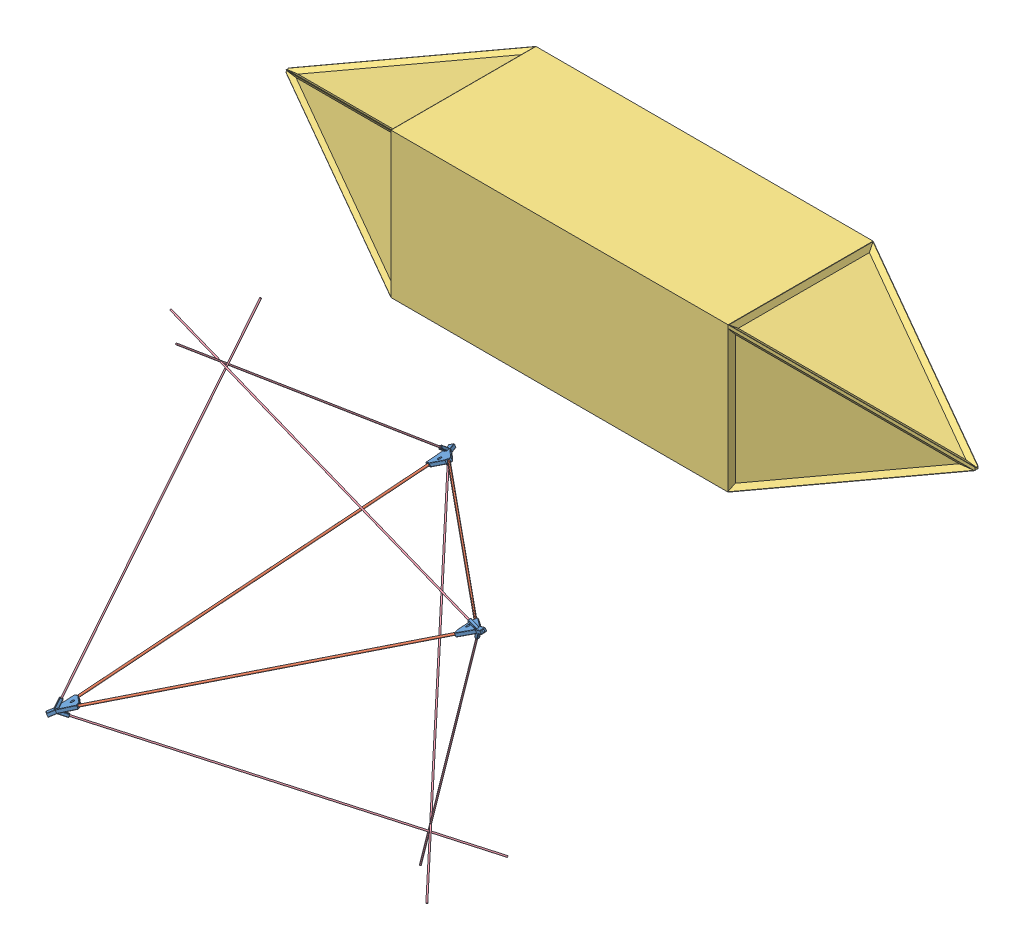
SolidWorks assembly Catastrophe, configuration Défaut. Lengths in mm.
Overall size (2044.4 1360.49 1572.81).
13 component instances, 4 part files, 22 mates.
Components (placement in the parent):
- pièceTriangle-1: pièceTriangle [Défaut] at (258.5913 881.7881 -1928.4174) x (0.355593 0.038555 0.933845) z (-0.425271 0.896403 0.124927) size (120.62 100 107.84)
- pièceTriangle-2: pièceTriangle [Défaut] at (138.1407 689.4914 -878.5931) x (0.542983 0.363125 -0.757172) z (0.425271 -0.896403 -0.124927) size (120.62 100 107.84)
- pièceTriangle-3: pièceTriangle [Défaut] at (1036.2836 1154.7713 -1239.8012) x (-0.898577 -0.40168 -0.176673) z (-0.425271 0.896403 0.124927) size (120.62 100 107.84)
- tigeCarboneCreux6mm-1: tigeCarboneCreux6mm [Défaut] at (170.0666 701.2426 -894.2555) x (-0.018642 -0.58195 -0.813011) z (0.832285 0.44156 -0.335151) size (6 6 1000)
- tigeCarboneCreux6mm-2: tigeCarboneCreux6mm [Défaut] at (281.732 894.6526 -1901.9281) x (0.592944 -0.70424 -0.390467) z (0.724095 0.25417 0.641158) size (6 6 1000)
- tigeCarboneCreux6mm-3: tigeCarboneCreux6mm [Défaut] at (254.9953 880.4678 -1891.1616) x (0.968307 0.20252 0.146174) z (-0.10819 -0.18739 0.976309) size (6 6 1000)
- BALLON-1: BALLON [Défaut] at (72.8102 1181.4731 -2370.9298) size (2044.4 430 430)
- tigeCarboneCreux4mm-1: tigeCarboneCreux4mm [Défaut] at (77.0413 1481.0125 -1283.4819) x (-0.319557 -0.946281 0.04935) z (0.947211 -0.317575 0.044011) size (4 4 1000)
- tigeCarboneCreux4mm-2: tigeCarboneCreux4mm [Défaut] at (262.1792 1563.0098 -1364.9594) x (-0.835891 -0.172075 -0.521226) z (-0.121324 -0.868182 0.481186) size (4 4 1000)
- tigeCarboneCreux4mm-3: tigeCarboneCreux4mm [Défaut] at (255.6801 893.6552 -1920.012) x (0.999492 0.01084 0.029969) z (-0.029969 0.639543 0.768171) size (4 4 1000)
- tigeCarboneCreux4mm-4: tigeCarboneCreux4mm [Défaut] at (834.7328 334.7724 -1524.6743) x (0.68437 0.603263 0.409526) z (-0.687147 0.345773 0.63896) size (4 4 1000)
- tigeCarboneCreux4mm-5: tigeCarboneCreux4mm [Défaut] at (262.4673 879.3979 -1921.9412) x (0.609548 0.77376 0.172469) z (0.548543 -0.56874 0.612891) size (4 4 1000)
- tigeCarboneCreux4mm-6: tigeCarboneCreux4mm [Défaut] at (644.551 252.2282 -1456.4429) x (0.877106 -0.285258 -0.386411) z (0.386411 0.896924 0.214973) size (4 4 1000)
Mates (geometry in assembly coordinates):
- Coaxiale1: concentric anti-aligned: cylinder of pièceTriangle-2 through (170.0666 701.2426 -894.2555) axis (0.832285 0.44156 -0.335151) radius 3; cylinder of tigeCarboneCreux6mm-1 through (1002.3517 1142.8026 -1229.4067) axis (-0.832285 -0.44156 0.335151) radius 3
- Coaxiale2: concentric aligned: cylinder of pièceTriangle-3 through (1002.3517 1142.8026 -1229.4067) axis (-0.832285 -0.44156 0.335151) radius 3; cylinder of tigeCarboneCreux6mm-1 through (1002.3517 1142.8026 -1229.4067) axis (-0.832285 -0.44156 0.335151) radius 3
- Coaxiale5: concentric anti-aligned: cylinder of pièceTriangle-1 through (254.9953 880.4678 -1891.1616) axis (-0.10819 -0.18739 0.976309) radius 3; cylinder of tigeCarboneCreux6mm-3 through (146.8055 693.0776 -914.8523) axis (0.10819 0.18739 -0.976309) radius 3
- Coaxiale7: concentric anti-aligned: cylinder of pièceTriangle-1 through (281.732 894.6526 -1901.9281) axis (0.724095 0.25417 0.641158) radius 3; cylinder of tigeCarboneCreux6mm-2 through (1005.8272 1148.8224 -1260.77) axis (-0.724095 -0.25417 -0.641158) radius 3
- Coaxiale8: concentric aligned: cylinder of pièceTriangle-3 through (1005.8272 1148.8224 -1260.77) axis (-0.724095 -0.25417 -0.641158) radius 3; cylinder of tigeCarboneCreux6mm-2 through (1005.8272 1148.8224 -1260.77) axis (-0.724095 -0.25417 -0.641158) radius 3
- Coaxiale9: concentric aligned: cylinder of pièceTriangle-2 through (146.8055 693.0776 -914.8523) axis (0.10819 0.18739 -0.976309) radius 3; cylinder of tigeCarboneCreux6mm-3 through (146.8055 693.0776 -914.8523) axis (0.10819 0.18739 -0.976309) radius 3
- Coïncidente12: coincident anti-aligned: plane of pièceTriangle-2 through (146.8055 693.0776 -914.8523) normal (0.10819 0.18739 -0.976309); plane of tigeCarboneCreux6mm-3 through (146.8055 693.0776 -914.8523) normal (-0.10819 -0.18739 0.976309)
- Coïncidente15: coincident anti-aligned: plane of pièceTriangle-2 through (170.0666 701.2426 -894.2555) normal (0.832285 0.44156 -0.335151); plane of tigeCarboneCreux6mm-1 through (170.0666 701.2426 -894.2555) normal (-0.832285 -0.44156 0.335151)
- Coïncidente16: coincident anti-aligned: plane of pièceTriangle-1 through (254.9953 880.4678 -1891.1616) normal (-0.10819 -0.18739 0.976309); plane of tigeCarboneCreux6mm-3 through (254.9953 880.4678 -1891.1616) normal (0.10819 0.18739 -0.976309)
- Coïncidente17: coincident anti-aligned: plane of pièceTriangle-3 through (1005.8272 1148.8224 -1260.77) normal (-0.724095 -0.25417 -0.641158); plane of tigeCarboneCreux6mm-2 through (1005.8272 1148.8224 -1260.77) normal (0.724095 0.25417 0.641158)
- Coaxiale10: concentric anti-aligned: cylinder of pièceTriangle-1 through (255.6801 893.6552 -1920.012) axis (-0.029969 0.639543 0.768171) radius 2.15; cylinder of tigeCarboneCreux4mm-3 through (225.7107 1533.198 -1151.8409) axis (0.029969 -0.639543 -0.768171) radius 2
- Coïncidente18: coincident anti-aligned: plane of pièceTriangle-1 through (255.6801 893.6552 -1920.012) normal (-0.029969 0.639543 0.768171); plane of tigeCarboneCreux4mm-3 through (255.6801 893.6552 -1920.012) normal (0.029969 -0.639543 -0.768171)
- Coaxiale14: concentric aligned: cylinder of pièceTriangle-2 through (140.8547 694.8275 -883.7736) axis (0.121324 0.868182 -0.481186) radius 2.15; cylinder of tigeCarboneCreux4mm-2 through (140.8547 694.8275 -883.7736) axis (0.121324 0.868182 -0.481186) radius 2
- Coïncidente20: coincident anti-aligned: plane of pièceTriangle-2 through (140.8547 694.8275 -883.7736) normal (0.121324 0.868182 -0.481186); plane of tigeCarboneCreux4mm-2 through (140.8547 694.8275 -883.7736) normal (-0.121324 -0.868182 0.481186)
- Coaxiale15: concentric aligned: cylinder of pièceTriangle-3 through (1024.2525 1163.4372 -1239.4711) axis (-0.947211 0.317575 -0.044011) radius 2.15; cylinder of tigeCarboneCreux4mm-1 through (1024.2525 1163.4372 -1239.4711) axis (-0.947211 0.317575 -0.044011) radius 2
- Coïncidente21: coincident anti-aligned: plane of pièceTriangle-3 through (1024.2525 1163.4372 -1239.4711) normal (-0.947211 0.317575 -0.044011); plane of tigeCarboneCreux4mm-1 through (1024.2525 1163.4372 -1239.4711) normal (0.947211 -0.317575 0.044011)
- Coaxiale16: concentric aligned: cylinder of pièceTriangle-3 through (1030.9616 1149.1525 -1241.4694) axis (-0.386411 -0.896924 -0.214973) radius 2.15; cylinder of tigeCarboneCreux4mm-6 through (1030.9616 1149.1525 -1241.4694) axis (-0.386411 -0.896924 -0.214973) radius 2
- Coïncidente22: coincident anti-aligned: plane of pièceTriangle-3 through (1030.9616 1149.1525 -1241.4694) normal (-0.386411 -0.896924 -0.214973); plane of tigeCarboneCreux4mm-6 through (1030.9616 1149.1525 -1241.4694) normal (0.386411 0.896924 0.214973)
- Coaxiale17: concentric anti-aligned: cylinder of pièceTriangle-1 through (262.4673 879.3979 -1921.9412) axis (0.548543 -0.56874 0.612891) radius 2.15; cylinder of tigeCarboneCreux4mm-5 through (811.0101 310.6582 -1309.0498) axis (-0.548543 0.56874 -0.612891) radius 2
- Coïncidente23: coincident anti-aligned: plane of pièceTriangle-1 through (262.4673 879.3979 -1921.9412) normal (0.548543 -0.56874 0.612891); plane of tigeCarboneCreux4mm-5 through (262.4673 879.3979 -1921.9412) normal (-0.548543 0.56874 -0.612891)
- Coaxiale18: concentric aligned: cylinder of pièceTriangle-2 through (147.586 680.5452 -885.7138) axis (0.687147 -0.345773 -0.63896) radius 2.15; cylinder of tigeCarboneCreux4mm-4 through (147.586 680.5452 -885.7138) axis (0.687147 -0.345773 -0.63896) radius 2
- Coïncidente24: coincident anti-aligned: plane of pièceTriangle-2 through (147.586 680.5452 -885.7138) normal (0.687147 -0.345773 -0.63896); plane of tigeCarboneCreux4mm-4 through (147.586 680.5452 -885.7138) normal (-0.687147 0.345773 0.63896)
